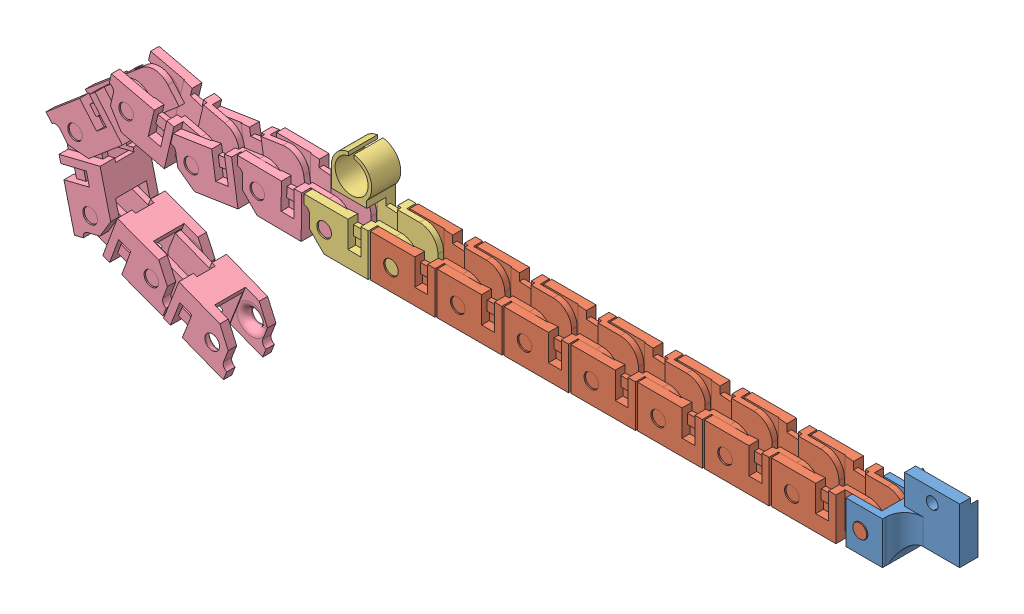
SolidWorks assembly Ensamblaje P3steel, configuration Predeterminado. Lengths in mm.
Overall size (239.96 64.41 16.76).
16 component instances, 4 part files, 38 mates.
Components (placement in the parent):
- Soporte cama-1: Soporte cama [Predeterminado] at (-37.1706 0.0661 21.153) x (0 0 1) z (1 0 0) size (13.26 19.84 25)
- Eslabon 5 Fijo-1: Eslabon 5 Fijo [Predeterminado] at (-53.1706 -11.4339 23.353) size (27.6 11.5 13)
- Eslabon 5 Fijo-2: Eslabon 5 Fijo [Predeterminado] at (-71.1706 -11.4339 23.553) size (27.6 11.5 13)
- Eslabon 5 Fijo-3: Eslabon 5 Fijo [Predeterminado] at (-89.1706 -11.4339 23.753) size (27.6 11.5 13)
- Eslabon 5 Fijo-4: Eslabon 5 Fijo [Predeterminado] at (-107.1706 -11.4339 23.953) size (27.6 11.5 13)
- Eslabon 5 Fijo-5: Eslabon 5 Fijo [Predeterminado] at (-125.1706 -11.4339 24.153) size (27.6 11.5 13)
- Eslabon 5 Fijo-6: Eslabon 5 Fijo [Predeterminado] at (-143.1706 -11.4339 24.353) size (27.6 11.5 13)
- Eslabon 5 Fijo-7: Eslabon 5 Fijo [Predeterminado] at (-161.1706 -11.4339 24.553) size (27.6 11.5 13)
- Eslabon 5 con soporte-1: Eslabon 5 con soporte [Predeterminado] at (-179.1706 -11.4339 24.753) size (27.5 22.46 13)
- Eslabon 5 Bloqueado-1: Eslabon 5 Bloqueado [Predeterminado] at (-197.2295 -11.2037 24.953) x (0.999945 -0.010447 0) z (0 0 1) size (27.5 11.5 13)
- Eslabon 5 Bloqueado-2: Eslabon 5 Bloqueado [Predeterminado] at (-214.0427 -14.5168 25.153) x (0.988426 0.151707 0) z (0 0 1) size (27.5 11.5 13)
- Eslabon 5 Bloqueado-3: Eslabon 5 Bloqueado [Predeterminado] at (-233.6929 -8.8041 25.353) x (0.973611 -0.228214 0) z (0 0 1) size (27.5 11.5 13)
- Eslabon 5 Bloqueado-4: Eslabon 5 Bloqueado [Predeterminado] at (-241.542 -22.7362 25.553) x (0.762531 0.646952 0) z (0 0 1) size (27.5 11.5 13)
- Eslabon 5 Bloqueado-5: Eslabon 5 Bloqueado [Predeterminado] at (-231.3608 -35.7468 25.753) x (-0.239469 0.970904 0) z (0 0 1) size (27.5 11.5 13)
- Eslabon 5 Bloqueado-6: Eslabon 5 Bloqueado [Predeterminado] at (-215.2732 -35.4828 25.953) x (-0.937844 0.347058 0) z (0 0 1) size (27.5 11.5 13)
- Eslabon 5 Bloqueado-7: Eslabon 5 Bloqueado [Predeterminado] at (-198.4347 -42.1249 26.153) x (-0.931636 0.363392 0) z (0 0 1) size (27.5 11.5 13)
Mates (geometry in assembly coordinates):
- Coincidente1: coincident anti-aligned: plane of Soporte cama-1 through (-37.1706 13.126 31.353) normal (0 0 -1); plane of Eslabon 5 Fijo-1 through (-37.1706 -9.9339 31.353) normal (0 0 1)
- Concéntrica1: concentric aligned: circle of Soporte cama-1; circle of Eslabon 5 Fijo-1
- Coincidente2: coincident aligned: plane of Soporte cama-1 through (-37.1706 -11.4339 21.153) normal (0 -1 0); plane of Eslabon 5 Fijo-1 through (-53.1706 -11.4339 23.353) normal (0 -1 0)
- Coincidente3: coincident anti-aligned: plane of Eslabon 5 Fijo-1 through (-53.1706 -19.4364 31.553) normal (0 0 -1); plane of Eslabon 5 Fijo-2 through (-55.1706 -9.9339 31.553) normal (0 0 1)
- Concéntrica2: concentric aligned: circle of Eslabon 5 Fijo-1; circle of Eslabon 5 Fijo-2
- Coincidente4: coincident aligned: plane of Eslabon 5 Fijo-1 through (-53.1706 -11.4339 23.353) normal (0 -1 0); plane of Eslabon 5 Fijo-2 through (-71.1706 -11.4339 23.553) normal (0 -1 0)
- Coincidente5: coincident anti-aligned: plane of Eslabon 5 Fijo-2 through (-71.1706 -19.4364 31.753) normal (0 0 -1); plane of Eslabon 5 Fijo-3 through (-73.1706 -9.9339 31.753) normal (0 0 1)
- Concéntrica3: concentric aligned: circle of Eslabon 5 Fijo-2; circle of Eslabon 5 Fijo-3
- Coincidente6: coincident aligned: plane of Eslabon 5 Fijo-2 through (-71.1706 -11.4339 23.553) normal (0 -1 0); plane of Eslabon 5 Fijo-3 through (-89.1706 -11.4339 23.753) normal (0 -1 0)
- Coincidente7: coincident anti-aligned: plane of Eslabon 5 Fijo-3 through (-89.1706 -19.4364 31.953) normal (0 0 -1); plane of Eslabon 5 Fijo-4 through (-91.1706 -9.9339 31.953) normal (0 0 1)
- Concéntrica4: concentric aligned: circle of Eslabon 5 Fijo-3; circle of Eslabon 5 Fijo-4
- Coincidente8: coincident aligned: plane of Eslabon 5 Fijo-3 through (-89.1706 -11.4339 23.753) normal (0 -1 0); plane of Eslabon 5 Fijo-4 through (-107.1706 -11.4339 23.953) normal (0 -1 0)
- Coincidente9: coincident anti-aligned: plane of Eslabon 5 Fijo-4 through (-107.1706 -19.4364 32.153) normal (0 0 -1); plane of Eslabon 5 Fijo-5 through (-109.1706 -9.9339 32.153) normal (0 0 1)
- Concéntrica5: concentric aligned: circle of Eslabon 5 Fijo-4; circle of Eslabon 5 Fijo-5
- Coincidente10: coincident aligned: plane of Eslabon 5 Fijo-4 through (-107.1706 -11.4339 23.953) normal (0 -1 0); plane of Eslabon 5 Fijo-5 through (-125.1706 -11.4339 24.153) normal (0 -1 0)
- Coincidente11: coincident anti-aligned: plane of Eslabon 5 Fijo-5 through (-125.1706 -19.4364 32.353) normal (0 0 -1); plane of Eslabon 5 Fijo-6 through (-127.1706 -9.9339 32.353) normal (0 0 1)
- Concéntrica6: concentric aligned: circle of Eslabon 5 Fijo-5; circle of Eslabon 5 Fijo-6
- Coincidente12: coincident aligned: plane of Eslabon 5 Fijo-5 through (-125.1706 -11.4339 24.153) normal (0 -1 0); plane of Eslabon 5 Fijo-6 through (-143.1706 -11.4339 24.353) normal (0 -1 0)
- Coincidente14: coincident anti-aligned: plane of Eslabon 5 Fijo-6 through (-143.1706 -19.4364 32.553) normal (0 0 -1); plane of Eslabon 5 Fijo-7 through (-145.1706 -9.9339 32.553) normal (0 0 1)
- Concéntrica7: concentric aligned: circle of Eslabon 5 Fijo-6; circle of Eslabon 5 Fijo-7
- Coincidente15: coincident aligned: plane of Eslabon 5 Fijo-6 through (-143.1706 -11.4339 24.353) normal (0 -1 0); plane of Eslabon 5 Fijo-7 through (-161.1706 -11.4339 24.553) normal (0 -1 0)
- Coincidente16: coincident anti-aligned: plane of Eslabon 5 Fijo-7 through (-161.1706 -19.4364 32.753) normal (0 0 -1); plane of Eslabon 5 con soporte-1 through (-163.1706 -9.9339 32.753) normal (0 0 1)
- Concéntrica8: concentric aligned: circle of Eslabon 5 Fijo-7; circle of Eslabon 5 con soporte-1
- Coincidente17: coincident aligned: plane of Eslabon 5 Fijo-7 through (-161.1706 -11.4339 24.553) normal (0 -1 0); plane of Eslabon 5 con soporte-1 through (-179.1706 -11.4339 24.753) normal (0 -1 0)
- Coincidente18: coincident anti-aligned: plane of Eslabon 5 con soporte-1 through (-179.1706 -19.4364 32.953) normal (0 0 -1); plane of Eslabon 5 Bloqueado-1 through (-181.2147 -9.871 32.953) normal (0 0 1)
- Concéntrica9: concentric aligned: circle of Eslabon 5 con soporte-1; circle of Eslabon 5 Bloqueado-1
- Coincidente19: coincident anti-aligned: plane of Eslabon 5 Bloqueado-1 through (-197.3131 -19.2058 33.153) normal (0 0 -1); plane of Eslabon 5 Bloqueado-2 through (-198.4554 -10.6069 33.153) normal (0 0 1)
- Concéntrica10: concentric aligned: circle of Eslabon 5 Bloqueado-1; circle of Eslabon 5 Bloqueado-2
- Coincidente21: coincident anti-aligned: plane of Eslabon 5 Bloqueado-2 through (-212.8286 -22.4267 33.353) normal (0 0 -1); plane of Eslabon 5 Bloqueado-3 through (-217.7728 -10.9951 33.353) normal (0 0 1)
- Concéntrica12: concentric aligned: circle of Eslabon 5 Bloqueado-2; circle of Eslabon 5 Bloqueado-3
- Coincidente23: coincident anti-aligned: plane of Eslabon 5 Bloqueado-3 through (-235.5192 -16.5954 33.553) normal (0 0 -1); plane of Eslabon 5 Bloqueado-4 through (-230.3119 -11.2412 33.553) normal (0 0 1)
- Concéntrica13: concentric aligned: circle of Eslabon 5 Bloqueado-3; circle of Eslabon 5 Bloqueado-4
- Concéntrica14: concentric aligned: circle of Eslabon 5 Bloqueado-4; circle of Eslabon 5 Bloqueado-5
- Coincidente26: coincident anti-aligned: plane of Eslabon 5 Bloqueado-5 through (-223.5911 -33.8304 33.953) normal (0 0 -1); plane of Eslabon 5 Bloqueado-6 through (-230.7993 -31.3366 33.953) normal (0 0 1)
- Concéntrica15: concentric aligned: circle of Eslabon 5 Bloqueado-5; circle of Eslabon 5 Bloqueado-6
- Coincidente27: coincident anti-aligned: plane of Eslabon 5 Bloqueado-6 through (-212.4959 -27.9777 34.153) normal (0 0 -1); plane of Eslabon 5 Bloqueado-7 through (-213.8859 -37.708 34.153) normal (0 0 1)
- Concéntrica16: concentric aligned: circle of Eslabon 5 Bloqueado-6; circle of Eslabon 5 Bloqueado-7
- Coincidente28: coincident: moEndPointRef_w of Eslabon 5 Bloqueado-4; plane of Eslabon 5 Bloqueado-5 through (-236.6487 -20.5715 33.753) normal (0 0 1)
